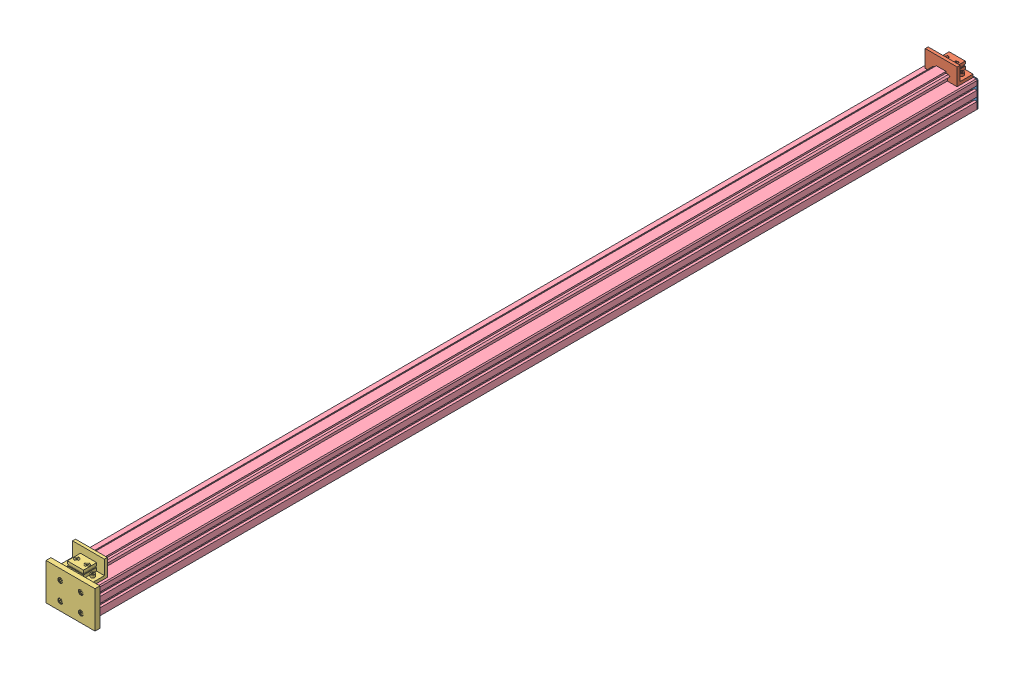
SolidWorks assembly without slider, configuration Default. Lengths in mm.
Overall size (100 100 1813.35).
4 component instances, 4 part files, 0 mates.
Components (placement in the parent):
- DLS3C_C-1: DLS3C_C [Default] at (0 27.5 -1800) x (0 0 -1) z (-1 0 0) size (3.35 55 80)
- DLS3C_B2-1: DLS3C_B2 [Default] at (0 0 -1799.6) x (-1 0 0) z (0 0 -1) size (65 45 32.8)
- DLS3C_B-1: DLS3C_B [Default] at origin size (100 100 42.8)
- DLS3C1800_(735)_B-1: DLS3C1800_(735)_B [Default] at origin size (80 70.95 1800)
